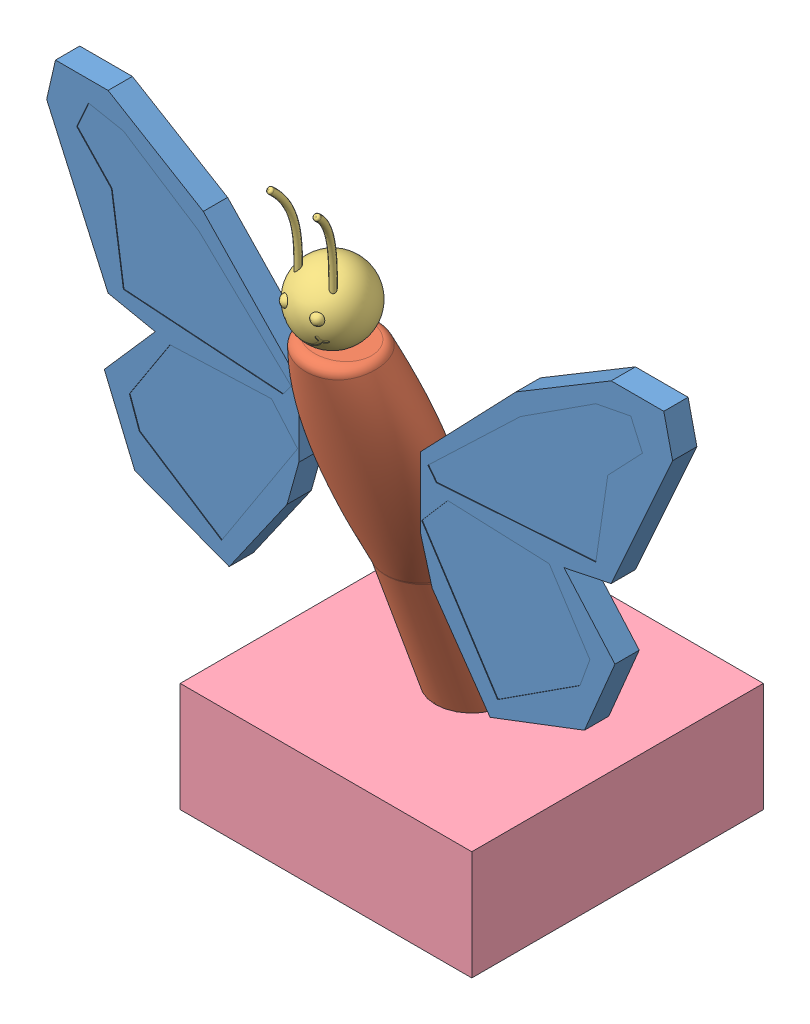
SolidWorks assembly butterfly_base, configuration Default. Lengths in mm.
Overall size (2617.43 2571.07 1359.12).
6 component instances, 4 part files, 2 mates.
Components (placement in the parent):
- butterfly-1: butterfly [Default] at (954.3499 1641.3317 1833.9497) size (2617.43 2113.87 901.92)
  - Wing-1: Wing [Default] at (371.665 221.4807 1594.4083) size (1207.07 1471.46 101.61)
  - Body-1: Body [Default] at (625.7054 -140.7403 1226.9822) size (574.9 1524 859.04)
  - Wing-2: Wing [Default] at (879.7459 221.4807 1696.0083) x (-1 0 0) z (0 0 -1) size (1207.07 1471.46 101.61)
  - Head-1: Head [Default] at (619.7065 1535.6597 1803.3329) size (304.8 589.87 325.57)
- Base-1: Base [Default] at (1580.0553 1043.3914 3060.932) size (1219.2 457.2 1269.48)
Mates (geometry in assembly coordinates):
- Coincident1: coincident: plane of butterfly-1/Body-1 through (1580.0553 1500.5914 3060.932) normal (0 -1 0); plane of Base-1 through (1599.7269 1500.5914 3494.1562) normal (0 1 0)
- Concentric3: concentric: circle of butterfly-1/Body-1; circle of Base-1
